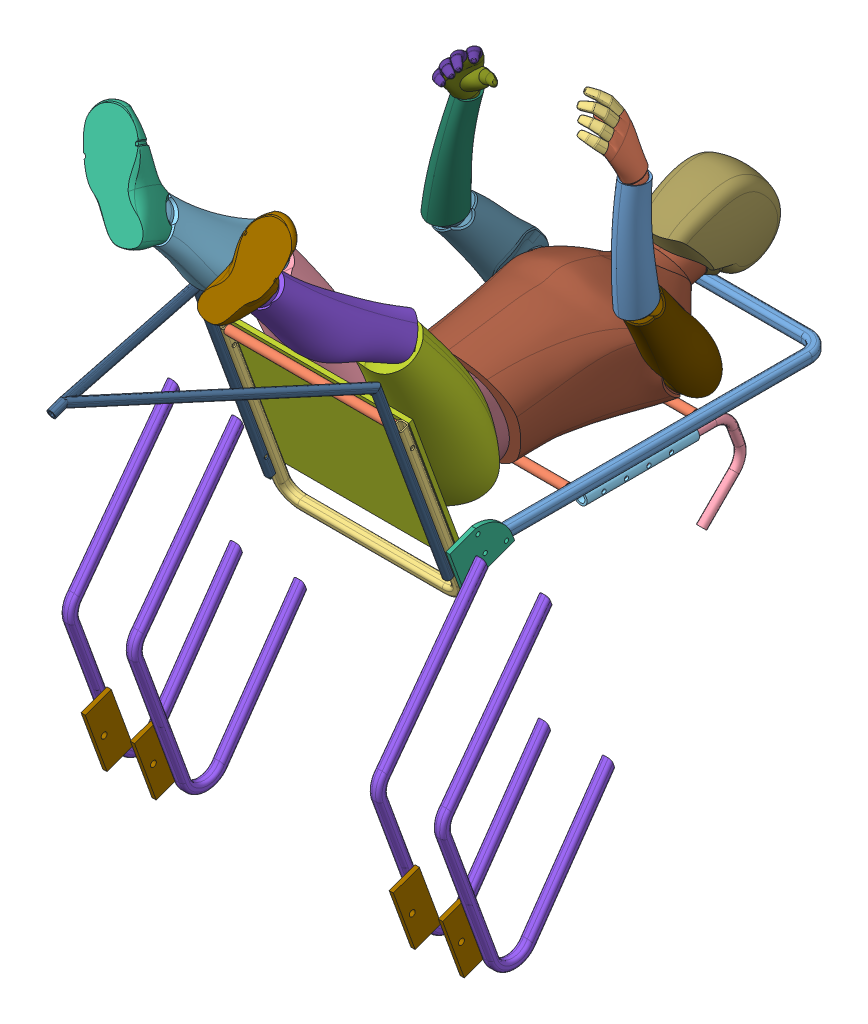
SolidWorks assembly noWheelTwoByOne, configuration Default. Lengths in mm.
Overall size (903.26 2050.35 1878.12).
43 component instances, 27 part files, 90 mates.
Components (placement in the parent):
- 02-23Back Seat Platform-U Beam-1: 02-23Back Seat Platform-U Beam [Default] at (-280.186 14.8002 533.2311) size (445 25 862.5)
- 02-23Circular Beam-1: 02-23Circular Beam [Default] at (-267.686 14.8002 -26.7689) size (395 20 20)
- 02-23Circular Beam-2: 02-23Circular Beam [Default] at (-267.686 14.8002 273.2311) size (395 20 20)
- 02-23Circular Beam-3: 02-23Circular Beam [Default] at (-267.686 344.0422 678.9348) x (1 0 0) z (0 -0.233979 0.972242) size (395 20 20)
- 02-23Seat Platform-1: 02-23Seat Platform [Default] at (-280.186 351.954 681.8144) x (0 0.939693 0.34202) z (-1 0 0) size (462.5 25 445)
- 02-23HANDLE Bar-1: 02-23HANDLE Bar [Default] at (139.814 -7.6998 159.7311) x (0 0.939693 0.34202) z (0 -0.34202 0.939693) size (273.13 20.68 248.34)
- 02-23Handle Bar Slot-1: 02-23Handle Bar Slot [Default] at (139.814 -187.6998 -58.438) x (0 0 1) z (0 -1 0) size (265 30 30)
- 02-23Handle Bar Slot-2: 02-23Handle Bar Slot [Default] at (-291.0833 172.3002 -58.438) x (0 0 1) z (0 1 0) size (265 30 30)
- 02-23HANDLE Bar-2: 02-23HANDLE Bar [Default] at (-291.0833 -7.6998 159.7311) x (0 0.939693 0.34202) z (0 -0.34202 0.939693) size (273.13 20.68 248.34)
- 02-23Hinge-3: 02-23Hinge [Default] at (-292.686 -37.5952 553.3323) x (0 0.939693 0.34202) z (0 -0.34202 0.939693) size (97.1 10 127)
- 02-23Hinge-4: 02-23Hinge [Default] at (162.314 -37.5952 553.3323) x (0 0.939693 0.34202) z (0 -0.34202 0.939693) size (97.1 10 127)
- 02-23Seat-2: 02-23Seat [Default] at (-70.186 181.1079 595.6875) x (0 0.939693 0.34202) z (1 0 0) size (380 10 439)
- Lower Wheel-1: Lower Wheel [Default] at (1087.3679 -325.4396 822.7234) x (0 0.939693 0.34202) z (-1 0 0) size (1385.23 813.57 177.26)
  - 02-23Lower Wheel Support-1: 02-23Lower Wheel Support [Default] at (-161.3811 20.8246 719.0539) x (1 0 0) z (0 -1 0) size (933.34 26.26 382.08)
  - 02-23Lower Wheel Support-2: 02-23Lower Wheel Support [Default] at (-161.3811 20.8246 870.0539) x (1 0 0) z (0 -1 0) size (933.34 26.26 382.08)
  - 02-23Wheel Platform-1: 02-23Wheel Platform [Default] at (-241.6519 -0.9066 731.5539) x (1 0 0) z (0 -1 0) size (1054.4 10 813.57)
  - 02-23Wheel Platform-3: 02-23Wheel Platform [Default] at (-241.6519 -0.9066 847.5539) x (1 0 0) z (0 -1 0) size (1054.4 10 813.57)
- Lower Wheel-2: Lower Wheel [Default] at (361.3679 -325.4396 822.7234) x (0 0.939693 0.34202) z (-1 0 0) size (1385.23 813.57 177.26)
  - 02-23Lower Wheel Support-1: 02-23Lower Wheel Support [Default] at (-161.3811 20.8246 719.0539) x (1 0 0) z (0 -1 0) size (933.34 26.26 382.08)
  - 02-23Lower Wheel Support-2: 02-23Lower Wheel Support [Default] at (-161.3811 20.8246 870.0539) x (1 0 0) z (0 -1 0) size (933.34 26.26 382.08)
  - 02-23Wheel Platform-1: 02-23Wheel Platform [Default] at (-241.6519 -0.9066 731.5539) x (1 0 0) z (0 -1 0) size (1054.4 10 813.57)
  - 02-23Wheel Platform-3: 02-23Wheel Platform [Default] at (-241.6519 -0.9066 847.5539) x (1 0 0) z (0 -1 0) size (1054.4 10 813.57)
- 02-23OneFreeWheel-1: 02-23OneFreeWheel [Left] at (-280.186 -11.1145 568.2914) x (0 0.939693 0.34202) z (0 -0.34202 0.939693) size (859.96 439 669.5)
- Articulated_Dummy-1: Articulated_Dummy [Default] at (-71.3146 59.1763 1362.0661) x (0.002657 -0.994892 -0.100914) z (0.000499 0.100916 -0.994895) size (1052.64 592.75 1430.49)
  - Torso-1: Torso [Default] at origin size (276.17 406.18 676.75)
  - Head-1: Head [Default] at (272.4966 0 13.9002) x (0.984808 0 0.173648) z (-0.173648 0 0.984808) size (223.51 154.11 248.99)
  - Pelvis-1: Pelvis [Default] at (-175.9416 -0.0047 21.1469) x (0.984808 0 -0.173648) z (0.173648 0 0.984808) size (220.9 294.19 237.82)
  - UpperArm_R-1: UpperArm_R [Default] at (-1164.6978 40.5521 782.9918) x (0.480784 0.0664 -0.874321) z (0.876833 -0.032757 0.479678) size (145.29 112.21 352.1)
  - LowerArm_R-1: LowerArm_R [Default] at (-1109.8206 -350.8514 1409.8475) x (-0.021504 -0.067308 -0.9975) z (0.939381 0.340144 -0.043203) size (97.1 110.82 304.02)
  - Hand_R-1: Hand_R [Default] at (-1026.554 -211.1082 756.2464) x (0.450032 0.495206 -0.74313) z (0.803724 0.138099 0.578754) size (143.51 200.25 239.15)
    - Hand_R-1: Hand_R [Default] at origin size (143.51 200.25 232.94)
    - Fingers_R-1: Fingers_R [Default] at origin size (103.08 62.21 73.67)
  - UpperArm_L-1: UpperArm_L [Default] at (-1154.4506 48.1192 789.555) x (0.383712 -0.421381 -0.821707) z (0.901636 -0.021319 0.431969) size (149.95 126.7 354.11)
  - LowerArm_L-1: LowerArm_L [Default] at (-1237.175 109.018 1373.4583) x (0.022959 0.087177 -0.995928) z (0.993849 -0.109941 0.013288) size (97.1 110.82 304.02)
  - Hand_L-1: Hand_L [Default] at (-1158.857 102.2382 896.6784) x (0.400695 -0.340847 -0.850451) z (0.891217 -0.070337 0.448091) size (143.54 200.25 239.15)
    - Hand_L-1: Hand_L [Default] at origin size (143.54 200.25 232.94)
    - Fingers_L-1: Fingers_L [Default] at origin size (103.08 62.28 73.68)
  - UpperLeg_R-1: UpperLeg_R [Default] at (-846.6749 137.4213 675.3146) x (0.202826 -0.686929 -0.697847) z (0.931594 -0.084173 0.35362) size (212.64 165.47 563.01)
  - LowerLeg_R-1: LowerLeg_R [Default] at (-769.3096 25.6211 503.3729) x (0.62768 -0.522628 -0.576956) z (0.723278 0.117422 0.6805) size (159.05 194.06 506.09)
  - Foot_R-1: Foot_R [Default] at (-744.6941 -0.9436 485.0971) x (0.785483 -0.333883 -0.521094) z (0.604301 0.232074 0.762209) size (250.01 160.41 191.51)
  - UpperLeg_L-1: UpperLeg_L [Default] at (-839.4632 -171.6805 657.1156) x (0.179608 0.724804 -0.665132) z (0.920043 0.115573 0.374385) size (212.64 165.47 563.01)
  - LowerLeg_L-1: LowerLeg_L [Default] at (-771.1336 -69.7092 493.1456) x (0.561883 0.655703 -0.504322) z (0.718877 -0.085418 0.689869) size (159.05 194.91 471.32)
  - Foot_L-1: Foot_L [Default] at (-730.9582 -37.7524 417.9636) x (0.868174 0.214838 -0.447345) z (0.453027 0.02488 0.89115) size (250.8 160.43 191.19)
Mates (geometry in assembly coordinates):
- Coincident1: coincident aligned: line of 02-23Back Seat Platform-U Beam-1 through (-280.186 14.8002 -26.7689) axis (1 0 0); line of 02-23Circular Beam-1 through (-267.686 14.8002 -26.7689) axis (1 0 0)
- Coincident2: coincident aligned: line of 02-23Back Seat Platform-U Beam-1 through (-280.186 14.8002 273.2311) axis (1 0 0); line of 02-23Circular Beam-2 through (-267.686 14.8002 273.2311) axis (1 0 0)
- Coincident3: coincident anti-aligned: plane of 02-23Back Seat Platform-U Beam-1 through (-267.686 10.3002 533.2311) normal (1 0 0); plane of 02-23Circular Beam-1 through (-267.686 14.8002 -26.7689) normal (-1 0 0)
- Coincident4: coincident anti-aligned: plane of 02-23Back Seat Platform-U Beam-1 through (-267.686 10.3002 533.2311) normal (1 0 0); plane of 02-23Circular Beam-2 through (-267.686 14.8002 273.2311) normal (-1 0 0)
- Parallel1: parallel aligned: line of 02-23Back Seat Platform-U Beam-1 through (139.814 14.8002 -276.7689) axis (0 0 1); line of 02-23Handle Bar Slot-1 through (139.814 -7.6998 -9.2689) axis (0 0 1)
- Perpendicular1: perpendicular: line of 02-23Back Seat Platform-U Beam-1 through (139.814 14.8002 123.2311) axis (0 -1 0); line of 02-23Handle Bar Slot-1 through (139.814 -7.6998 -9.2689) axis (0 0 1)
- Parallel3: parallel aligned: line of 02-23Handle Bar Slot-1 through (139.814 -7.6998 -9.2689) axis (0 0 1); line of 02-23Handle Bar Slot-2 through (-291.0833 -7.6998 -9.2689) axis (0 0 1)
- Distance2: distance = 25 mm: line of 02-23Back Seat Platform-U Beam-1 through (-280.186 14.8002 533.2311) axis (0 0 -1); line of 02-23Handle Bar Slot-2 through (-291.0833 -7.6998 -9.2689) axis (0 0 1)
- Coincident16: coincident anti-aligned: point of Back Seat Platform-U Beam-1; unknown of Handle Bar Slot-1
- Coincident17: coincident anti-aligned: line of 02-23Back Seat Platform-U Beam-1 through (139.814 14.8002 123.2311) axis (0 -1 0); line of 02-23Handle Bar Slot-1 through (139.814 -7.6998 123.2311) axis (0 1 0)
- Concentric1: concentric anti-aligned: cylinder of 02-23HANDLE Bar-1 through (139.814 -7.6998 159.7311) axis (0 0 -1) radius 10; cylinder of 02-23Handle Bar Slot-1 through (139.814 -7.6998 -9.2689) axis (0 0 1) radius 10
- Concentric2: concentric anti-aligned: cylinder of 02-23Handle Bar Slot-2 through (-291.0833 -7.6998 -9.2689) axis (0 0 1) radius 10; cylinder of 02-23HANDLE Bar-2 through (-291.0833 -7.6998 159.7311) axis (0 0 -1) radius 10
- Coincident25: coincident anti-aligned: circle of Wheel Platform-1; circle of Wheel-1
- Coincident26: coincident aligned: circle of Wheel-1; circle of Wheel Platform-2
- Parallel9: parallel aligned: line of 02-23Circular Beam-3 through (-267.686 344.0422 678.9348) axis (1 0 0); line of 02-23Seat Platform-1 through (-280.186 304.9694 664.7134) axis (1 0 0)
- Coincident39: coincident: unknown of 02-23Circular Beam-3; plane of 02-23Seat Platform-1 through (-267.686 350.4149 686.043) normal (1 0 0)
- Coincident40: coincident: unknown of 02-23Circular Beam-3; line of 02-23Seat Platform-1 through (-267.686 351.954 681.8144) axis (0 -0.939693 -0.34202)
- Coincident41: coincident: line of 02-23Circular Beam-3 through (-267.686 344.0422 678.9348) axis (1 0 0)
- Coincident42: coincident: line of 02-23Circular Beam-3 through (-267.686 344.0422 678.9348) axis (1 0 0)
- Parallel12: parallel aligned: plane of 02-23Seat Platform-1 through (-284.686 356.2293 670.0683) normal (0 0.34202 -0.939693); plane of 02-21Free Wheel Leg-2 through (141.314 261.234 638.6853) normal (0 0.34202 -0.939693)
- Parallel13: parallel aligned: plane of 02-23Seat Platform-1 through (-284.686 356.2293 670.0683) normal (0 0.34202 -0.939693); plane of 02-21Free Wheel Leg-1 through (-278.686 261.234 638.6853) normal (0 0.34202 -0.939693)
- Coincident53: coincident aligned: line of 02-23Seat Platform-1 through (-292.686 -31.7809 537.3575) axis (0 -0.34202 0.939693); line of 02-23Hinge-3 through (-292.686 5.8414 433.9914) axis (0 -0.34202 0.939693)
- Coincident54: coincident aligned: plane of 02-23Seat Platform-1 through (-284.686 347.6788 693.5606) normal (0 -0.34202 0.939693); plane of 02-23Hinge-3 through (-302.686 -37.5952 553.3323) normal (0 -0.34202 0.939693)
- Coincident55: coincident aligned: line of 02-23Seat Platform-1 through (152.314 -31.7809 537.3575) axis (0 -0.34202 0.939693); line of 02-23Hinge-4 through (152.314 5.8414 433.9914) axis (0 -0.34202 0.939693)
- Coincident56: coincident aligned: plane of 02-23Seat Platform-1 through (-284.686 347.6788 693.5606) normal (0 -0.34202 0.939693); plane of 02-23Hinge-4 through (152.314 -37.5952 553.3323) normal (0 -0.34202 0.939693)
- Coincident57: coincident anti-aligned: circle of Back Seat Platform-U Beam-1; circle of Hinge-4
- Coincident58: coincident anti-aligned: circle of Back Seat Platform-U Beam-1; circle of Hinge-4
- Coincident66: coincident anti-aligned: plane of 02-23Seat Platform-1 through (-284.686 356.2293 670.0683) normal (0 0.34202 -0.939693); plane of 02-23Seat-2 through (-70.186 177.6877 605.0844) normal (0 -0.34202 0.939693)
- Parallel14: parallel aligned: plane of 02-23Seat Platform-1 through (152.314 -34.859 545.8148) normal (1 0 0); plane of 02-23Seat-2 through (149.314 -0.8539 540.1006) normal (1 0 0)
- Coincident68: coincident aligned: plane of 02-23Seat Platform-1 through (144.314 353.4931 677.5858) normal (0 0.939693 0.34202); plane of 02-23Seat-2 through (149.314 356.2293 670.0683) normal (0 0.939693 0.34202)
- Concentric3: concentric aligned: cylinder of 02-23HANDLE Bar-1 through (149.814 -7.6998 109.7311) axis (-1 0 0) radius 5; cylinder of 02-23Handle Bar Slot-1 through (154.814 -7.6998 109.7311) axis (-1 0 0) radius 5
- Concentric4: concentric anti-aligned: cylinder of 02-23Handle Bar Slot-1 through (154.814 -7.6998 109.7311) axis (-1 0 0) radius 5; cylinder of 02-23Handle Bar Slot-2 through (-306.0833 -7.6998 109.7311) axis (1 0 0) radius 5
- Concentric5: concentric anti-aligned: cylinder of 02-23Handle Bar Slot-2 through (-306.0833 -7.6998 109.7311) axis (1 0 0) radius 5; cylinder of 02-23HANDLE Bar-2 through (-281.0833 -7.6998 109.7311) axis (-1 0 0) radius 5
- Concentric6: concentric anti-aligned: cylinder of 02-23Back Seat Platform-U Beam-1 through (-292.686 14.8002 503.2311) axis (1 0 0) radius 5; cylinder of 02-23Hinge-3 through (-292.686 14.8002 503.2311) axis (-1 0 0) radius 5
- Parallel20: parallel aligned: line of Lower Wheel Support-1 through (-143.3064 342.5505 678.3918) axis (0 0.422618 0.906308); line of Lower Wheel Support-2 through (1.6936 342.5505 678.3918) axis (0 0.422618 0.906308)
- Coincident78: coincident aligned: line of Lower Wheel Support-1 through (-130.8064 -388.705 683.2525) axis (0 0.939693 0.34202); line of Wheel Platform-1 through (-130.8064 -378.8383 686.8437) axis (0 0.939693 0.34202)
- Coincident79: coincident aligned: line of Wheel Platform-2 through (-10.8064 -378.8383 686.8437) axis (0 0.939693 0.34202); line of Lower Wheel Support-2 through (-10.8064 -388.705 683.2525) axis (0 0.939693 0.34202)
- Coincident83: coincident anti-aligned: plane of 02-23Seat Platform-1 through (-284.686 355.2032 672.8873) normal (0 -0.34202 0.939693); plane of 02-21Free Wheel Leg-1 through (-278.686 261.234 638.6853) normal (0 0.34202 -0.939693)
- Coincident84: coincident anti-aligned: plane of 02-23Seat Platform-1 through (-289.686 350.4149 686.043) normal (1 0 0); plane of 02-21Free Wheel Leg-1 through (-289.686 257.4717 649.0219) normal (-1 0 0)
- Coincident85: coincident anti-aligned: plane of 02-23Seat Platform-1 through (-284.686 355.2032 672.8873) normal (0 -0.34202 0.939693); plane of 02-21Free Wheel Leg-2 through (141.314 261.234 638.6853) normal (0 0.34202 -0.939693)
- Coincident86: coincident anti-aligned: plane of 02-23Seat Platform-1 through (149.314 -34.859 545.8148) normal (-1 0 0); plane of 02-21Free Wheel Leg-2 through (149.314 257.4717 649.0219) normal (1 0 0)
- Coincident89: coincident aligned: plane of 02-21Free Wheel Leg-1 through (-278.686 407.5601 693.1019) normal (0 0.984808 -0.173648); plane of 02-21Free Wheel Leg-2 through (141.314 407.5601 693.1019) normal (0 0.984808 -0.173648)
- Coincident94: coincident: line of Lower Wheel Support-1 through (-120.8064 -309.9004 716.7238) axis (0 -0.34202 0.939693)
- Coincident95: coincident aligned: line of 02-23Seat Platform-1 through (-143.3064 -70.9077 527.9054) axis (0 -0.34202 0.939693); line of Lower Wheel Support-1 through (-143.3064 -74.0445 536.5239) axis (0 -0.34202 0.939693)
- Parallel21: parallel aligned: line of 02-23Seat Platform-1 through (1.6936 -70.9077 527.9054) axis (0 -0.34202 0.939693); line of Lower Wheel Support-2 through (1.6936 -74.0445 536.5239) axis (0 -0.34202 0.939693)
- Coincident98: coincident aligned: line of Lower Wheel Support-1 through (-138.8064 -359.1911 552.459) axis (-1 0 0); line of Lower Wheel Support-2 through (6.1936 -359.1911 552.459) axis (-1 0 0)
- Parallel26: parallel anti-aligned: line of Lower Wheel Support-1 through (-120.8064 -309.9004 716.7238) axis (0 -0.34202 0.939693); line of 02-21Free Wheel Leg-1 through (-280.186 -329.3807 853.1591) axis (0 0.34202 -0.939693)
- Distance3: distance = 734.3042 mm: point of ?; point of ?
- Concentric7: concentric aligned: cylinder of 02-21Free Wheel Leg-1 through (-262.686 328.4042 1092.5732) axis (-1 0 0) radius 5; cylinder of Free Wheel-1 through (-272.686 283.4237 1135.7514) axis (-1 0 0) radius 5
- Coincident100: coincident: line of 02-21Free Wheel Leg-1 through (-280.186 328.9197 1095.497) axis (0 0.173648 0.984808)
- Concentric9: concentric aligned: cylinder of 02-23Seat Platform-1 through (152.314 304.9694 664.7134) axis (-1 0 0) radius 5; cylinder of 02-21Free Wheel Leg-1 through (-270.686 304.9694 664.7134) axis (-1 0 0) radius 5
- Parallel31: parallel anti-aligned: plane of 02-23Seat Platform-1 through (-284.686 347.6788 693.5606) normal (0 -0.34202 0.939693); plane of Lower Wheel-1/02-23Lower Wheel Support-1 through (372.814 -346.0302 420.6057) normal (0 0.34202 -0.939693)
- Parallel32: parallel anti-aligned: plane of 02-23Seat Platform-1 through (-284.686 347.6788 693.5606) normal (0 -0.34202 0.939693); plane of Lower Wheel-1/02-23Lower Wheel Support-2 through (221.814 -346.0302 420.6057) normal (0 0.34202 -0.939693)
- Coincident105: coincident: plane of 02-23Seat Platform-1 through (-240.186 -84.1929 527.8587) normal (0 -0.939693 -0.34202); line of Lower Wheel-1/02-23Lower Wheel Support-1 through (363.814 -315.7932 452.0765) axis (1 0 0)
- Coincident106: coincident: plane of 02-23Seat Platform-1 through (-240.186 -84.1929 527.8587) normal (0 -0.939693 -0.34202); line of Lower Wheel-1/02-23Lower Wheel Support-2 through (212.814 -315.7932 452.0765) axis (1 0 0)
- Coincident110: coincident anti-aligned: circle of 02-21Seat Platform-1; circle of 02-21Free Wheel Leg-1
- Coincident111: coincident anti-aligned: plane of 02-23Seat Platform-1 through (-284.686 355.2032 672.8873) normal (0 -0.34202 0.939693); plane of 02-21Free Wheel Leg-1 through (-278.686 261.234 638.6853) normal (0 0.34202 -0.939693)
- Concentric11: concentric aligned: cylinder of 02-23Seat Platform-1 through (152.314 304.9694 664.7134) axis (-1 0 0) radius 5; cylinder of 02-21Free Wheel Leg-3 through (-270.686 304.9694 664.7134) axis (-1 0 0) radius 5
- Coincident112: coincident anti-aligned: plane of 02-23Seat Platform-1 through (-284.686 355.2032 672.8873) normal (0 -0.34202 0.939693); plane of 02-21Free Wheel Leg-3 through (-278.686 261.234 638.6853) normal (0 0.34202 -0.939693)
- Coincident113: coincident anti-aligned: plane of 02-23Seat Platform-1 through (-289.686 350.4149 686.043) normal (1 0 0); plane of 02-21Free Wheel Leg-3 through (-289.686 257.4717 649.0219) normal (-1 0 0)
- Parallel27: parallel anti-aligned: plane of 02-21Free Wheel Leg-3 through (-479.2268 393.3597 1260.8991) normal (0 -0.34202 0.939693); plane of 02-21Free Wheel Bracket-1 through (-511.8941 407.7106 1266.1224) normal (0 0.34202 -0.939693)
- Coincident116: coincident: unknown of ?; line of ? through (-482.0205 410.2964 1267.0635) axis (0.091725 -0.935731 -0.340578)
- Coincident117: coincident: unknown of ?; line of ? through (-510.0596 388.9959 1259.3108) axis (0.995784 0.086193 0.031372)
- Coincident120: coincident: point of ?; point of ?
- Coincident121: coincident: point of ?; point of ?
- Coincident122: coincident anti-aligned: circle of 02-21Seat Platform-1; circle of 02-21(Left)Free Wheel Leg-1
- Coincident123: coincident anti-aligned: plane of 02-23Seat Platform-1 through (-284.686 355.2032 672.8873) normal (0 -0.34202 0.939693); plane of 02-21(Left)Free Wheel Leg-1 through (-278.686 261.234 638.6853) normal (0 0.34202 -0.939693)
- Coincident125: coincident anti-aligned: plane of 02-21Free Wheel Bracket-1 through (-511.8941 407.7106 1266.1224) normal (0 0.34202 -0.939693); plane of 02-21(Left)Free Wheel Leg-1 through (-479.2268 393.3597 1260.8991) normal (0 -0.34202 0.939693)
- Coincident126: coincident: line of 02-21Free Wheel Bracket-1 through (-482.0205 410.2964 1267.0635) axis (0.091725 -0.935731 -0.340578)
- Coincident127: coincident: line of 02-21Free Wheel Bracket-1 through (-510.0596 388.9959 1259.3108) axis (0.995784 0.086193 0.031372)
- Coincident128: coincident anti-aligned: circle of 02-21Seat Platform-1; circle of 02-21(Right)Free Wheel Leg-1
- Coincident129: coincident anti-aligned: plane of 02-23Seat Platform-1 through (-284.686 355.2032 672.8873) normal (0 -0.34202 0.939693); plane of 02-21(Right)Free Wheel Leg-1 through (141.314 261.234 638.6853) normal (0 0.34202 -0.939693)
- Parallel29: parallel anti-aligned: plane of 02-23Seat Platform-1 through (-284.686 347.6788 693.5606) normal (0 -0.34202 0.939693); plane of Lower Wheel-2/02-23Lower Wheel Support-1 through (-353.186 -346.0302 420.6057) normal (0 0.34202 -0.939693)
- Parallel28: parallel anti-aligned: plane of 02-23Seat Platform-1 through (-284.686 347.6788 693.5606) normal (0 -0.34202 0.939693); plane of Lower Wheel-2/02-23Lower Wheel Support-2 through (-504.186 -346.0302 420.6057) normal (0 0.34202 -0.939693)
- Coincident139: coincident: plane of 02-23Seat Platform-1 through (-240.186 -84.1929 527.8587) normal (0 -0.939693 -0.34202); line of Lower Wheel-2/02-23Lower Wheel Support-1 through (-162.186 -86.9291 535.3763) axis (1 0 0)
- Coincident140: coincident: plane of 02-23Seat Platform-1 through (-240.186 -84.1929 527.8587) normal (0 -0.939693 -0.34202); line of Lower Wheel-2/02-23Lower Wheel Support-2 through (-313.186 -86.9291 535.3763) axis (1 0 0)
- Parallel34: parallel: plane of 02-23Seat Platform-1 through (-284.686 355.2032 672.8873) normal (0 -0.34202 0.939693); plane of 02-23OneFreeWheel-1 through (-278.686 -1.88 542.9197) normal (0 0.34202 -0.939693)
- Coincident142: coincident: plane of 02-23Seat Platform-1 through (-289.686 350.4149 686.043) normal (1 0 0); plane of 02-23OneFreeWheel-1 through (-289.686 -5.6422 553.2563) normal (-1 0 0)
- Lateral distance between Main wheels: distance = 550 mm anti-aligned: plane of Lower Wheel-1/02-23Lower Wheel Support-2 through (204.814 -354.4874 417.5276) normal (-1 0 0); plane of Lower Wheel-2/02-23Lower Wheel Support-1 through (-345.186 -354.4874 417.5276) normal (1 0 0)
- Width1: width anti-aligned: plane of 02-23Seat-2 through (-289.686 -0.8539 540.1006) normal (-1 0 0); plane of 02-23Seat-2 through (149.314 -0.8539 540.1006) normal (1 0 0); plane of Lower Wheel-1/02-23Wheel Platform-1 through (355.814 -552.8282 740.9255) normal (1 0 0); plane of Lower Wheel-2/02-23Wheel Platform-3 through (-496.186 -552.8282 740.9255) normal (-1 0 0)
- Width2: width aligned: plane of 02-23Seat-2 through (-289.686 -0.8539 540.1006) normal (-1 0 0); plane of 02-23Seat-2 through (149.314 -0.8539 540.1006) normal (1 0 0); plane of 02-23Seat Platform-1 through (-292.686 350.4149 686.043) normal (-1 0 0); plane of 02-23Seat Platform-1 through (152.314 -34.859 545.8148) normal (1 0 0)
- Back of seat to Main wheel: distance = 450 mm: plane of 02-23Seat-2 through (149.314 -0.8539 540.1006) normal (0 -0.939693 -0.34202); line of Lower Wheel-2/02-23Wheel Platform-3 through (-486.186 -557.1035 752.6717) axis (0 0.34202 -0.939693)
- Back of seat to Free Wheel: distance = 800 mm: plane of 02-23Seat-2 through (149.314 -0.8539 540.1006) normal (0 -0.939693 -0.34202); line of 02-23OneFreeWheel-1 through (-280.186 740.6396 841.9075) axis (1 0 0)
- Coincident153: coincident anti-aligned: plane of 02-23Back Seat Platform-U Beam-1 through (-280.186 14.8002 533.2311) normal (0 1 0); plane of Articulated_Dummy-1 through (-70.186 14.8002 33.6283) normal (0 -1 0)
- Coincident154: coincident aligned: plane of 02-23Seat-2 through (-70.186 181.1079 595.6875) normal (1 0 0); plane of Articulated_Dummy-1 through (-70.186 59.1763 1362.0661) normal (1 0 0)
- Tangent1: tangent anti-aligned: plane of 02-23Seat-2 through (-70.186 181.1079 595.6875) normal (0 0.34202 -0.939693); face of Articulated_Dummy-1/Pelvis-1
- Top of seat to Main wheel: distance = 400 mm: line of Lower Wheel-2/02-23Wheel Platform-3 through (-486.186 -557.1035 752.6717) axis (0 0.939693 0.34202); plane of 02-23Seat-2 through (-70.186 181.1079 595.6875) normal (0 0.34202 -0.939693)
- Coincident156: coincident aligned: plane of Lower Wheel-1/02-23Wheel Platform-3 through (229.814 -634.4208 745.814) normal (0 -0.939693 -0.34202); plane of Lower Wheel-2/02-23Wheel Platform-1 through (-380.186 -634.4208 745.814) normal (0 -0.939693 -0.34202)
- Coincident157: coincident aligned: plane of Lower Wheel-1/02-23Wheel Platform-3 through (229.814 -634.4208 745.814) normal (0 -0.34202 0.939693); plane of Lower Wheel-2/02-23Wheel Platform-1 through (-380.186 -634.4208 745.814) normal (0 -0.34202 0.939693)
- Top of seat to Free wheel: distance = 700 mm: line of 02-23OneFreeWheel-1 through (-70.186 514.9063 1462.1046) axis (0 -0.939693 -0.34202); plane of 02-23Seat-2 through (-70.186 181.1079 595.6875) normal (0 0.34202 -0.939693)
